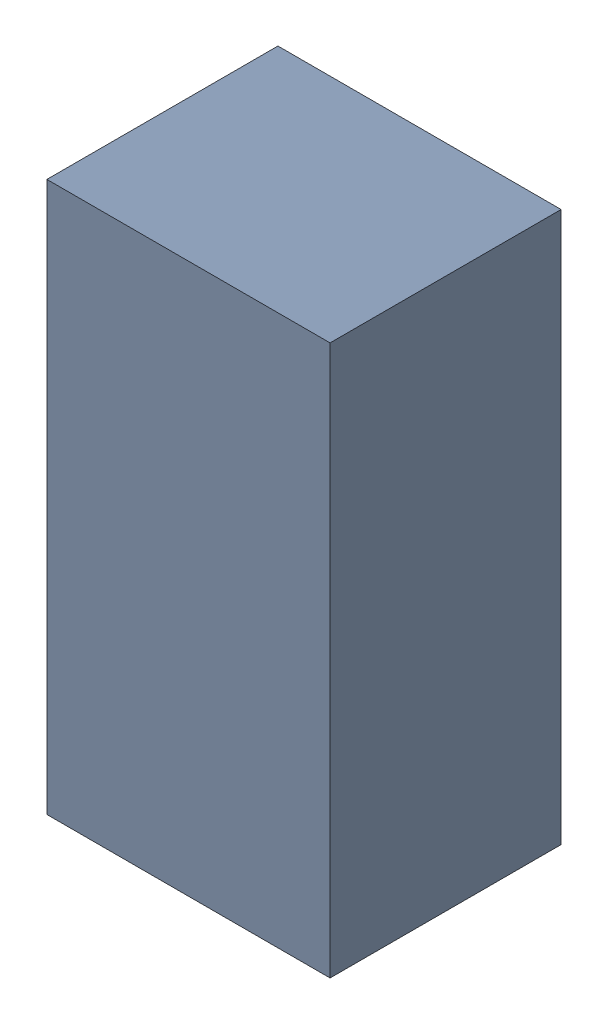
SolidWorks assembly FBead_Murata_BLM18EG221SN1D_eec.step, configuration Default. Lengths in mm.
Overall size (17 33.02 13.87).
4 component instances, 3 part files, 0 mates.
Components (placement in the parent):
- Body.step-1: Body.step [Default] x (-1 0 0) z (0 0 1) size (17 33.02 13.87)
- side.step-1: side.step [Default] at (-0.5 0.4917 0) x (-1 0 0) z (0 0 1) size (0.4 0.8 0.95)
- side.step-2: side.step [Default] at (0.5 0.4917 0.95) x (1 0 0) z (0 0 -1) size (0.4 0.8 0.95)
- Murata.step-1: Murata.step [Default] at (-0.8876 -0.696 0.892) size (0.61 0.14 0.03)
